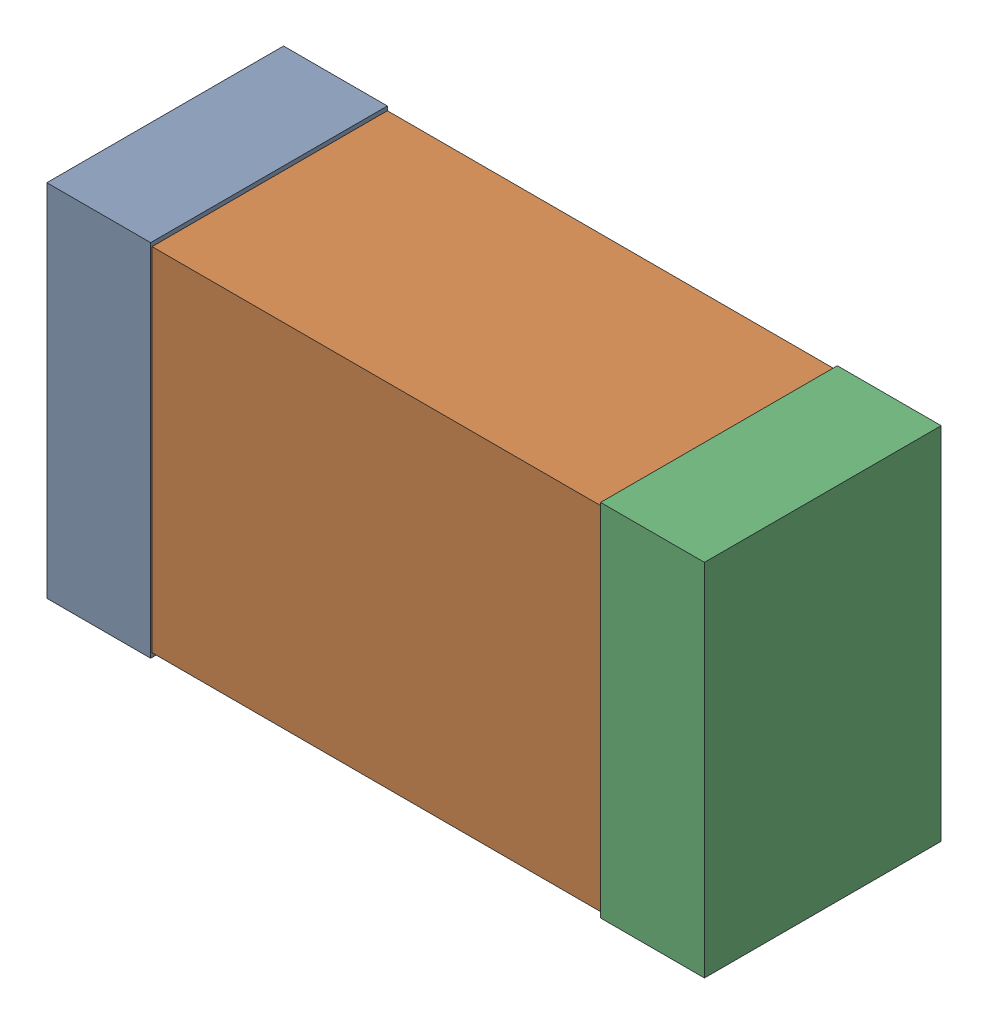
SolidWorks assembly C9Kanaloa_v2.0.0_Motor, configuration Default. Lengths in mm.
Overall size (2.38 1.3 0.85).
6 component instances, 2 part files, 0 mates.
Components (placement in the parent):
- 352877648-1: 352877648 [Default] at (61.4586 123.4186 0) size (0.38 1.3 0.85)
  - Extruded_14-1: Extruded_14 [Default] at origin size (0.38 1.3 0.85)
- 352877904-1: 352877904 [Default] at (62.4586 123.4186 0) size (2.2 1.27 0.85)
  - Extruded_18-1: Extruded_18 [Default] at origin size (2.2 1.27 0.85)
- 352877648-2: 352877648 [Default] at (63.4586 123.4186 0) size (0.38 1.3 0.85)
  - Extruded_14-1: Extruded_14 [Default] at origin size (0.38 1.3 0.85)
